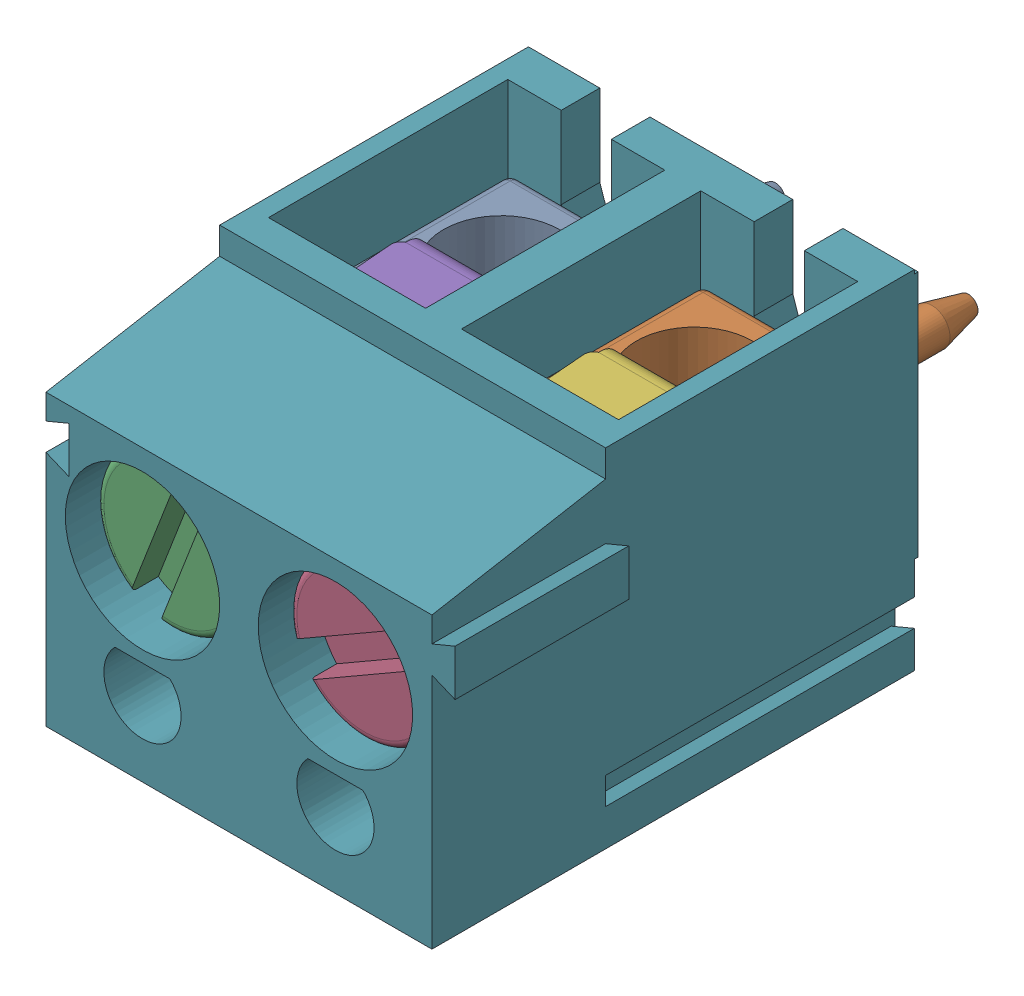
SolidWorks assembly J1, configuration Default. Lengths in mm.
Overall size (11.2 9 16.4).
8 component instances, 4 part files, 0 mates.
Components (placement in the parent):
- 691101710002-1: 691101710002 [Default] at (19.8119 56.6419 0) x (-1 0 0) z (0 0 1) size (11.2 9 16.4)
  - 691101710002_1-1: 691101710002_1 [Default] at (2.5 0 4) size (3.95 4 10.9)
  - 691101710002_1-2: 691101710002_1 [Default] at (-2.5 0 4) size (3.95 4 10.9)
  - 691101710002_4-1: 691101710002_4 [Default] at (2.5 0.0307 11.75) x (0.93283 -0.360317 0) z (0 0 1) size (3.9 3.9 7.08)
  - 691101710002_4-2: 691101710002_4 [Default] at (-2.5 0 11.75) x (0.5 -0.866025 0) z (0 0 1) size (3.9 3.9 7.08)
  - 691101710002_2-1: 691101710002_2 [Default] at (2.5 0.0307 7.2) size (3.95 5.03 4.22)
  - 691101710002_2-2: 691101710002_2 [Default] at (-2.5 0 7.2) size (3.95 5.03 4.22)
  - 691101710002_3-1: 691101710002_3 [Default] at origin size (11.2 9 12.6)
